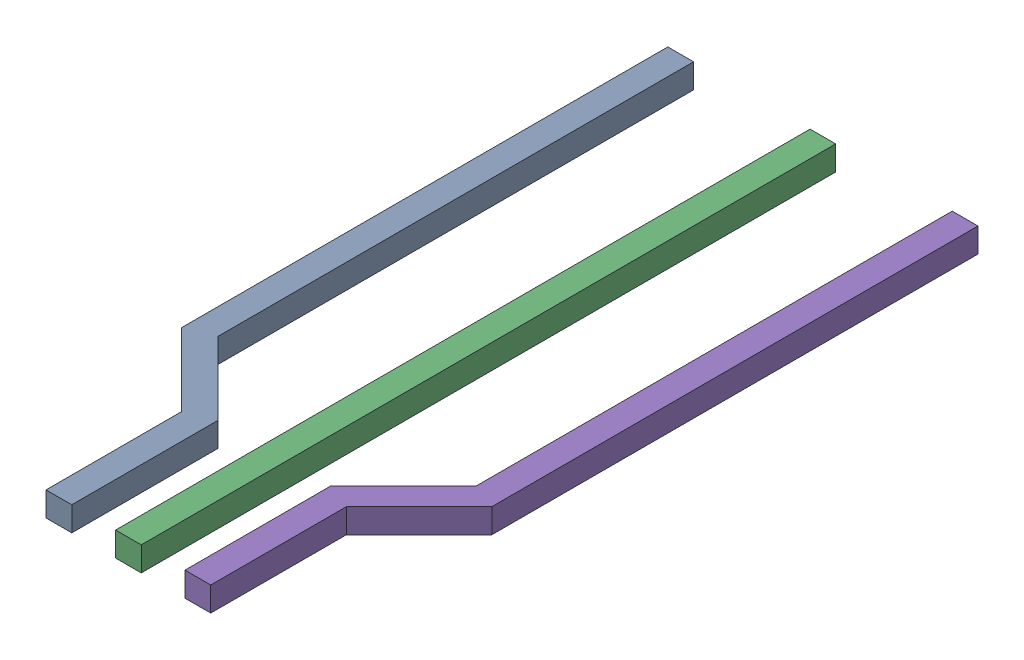
SolidWorks assembly Free-Models.step, configuration Default. Lengths in mm.
Overall size (5.68 0.46 12.71).
15 component instances, 4 part files, 0 mates.
Components (placement in the parent):
- PCB1.step-1: PCB1.step [Default] at (-1.2706 -0.1276 0) x (1 0 0) z (0 -1 0) size (1.81 12.71 0.46)
  - Free-Models-1.step-1: Free-Models-1.step [Default] at origin size (1.81 12.71 0.46)
    - 523779104.step-1: 523779104.step [Default] at (-0.665 -6.35 -0.35) size (1.81 12.71 0.46)
      - Extruded-43.step-1: Extruded-43.step [Default] at origin size (1.81 12.71 0.46)
  - Board-44.step-1: Board-44.step [Default] at (0 0 -0.2083) size (0.27 0.27 0.21)
- PCB2.step-1: PCB2.step [Default] at (0.0004 -0.1275 0) x (1 0 0) z (0 -1 0) size (0.47 12.7 0.45)
  - Free-Models-2.step-1: Free-Models-2.step [Default] at origin size (0.47 12.7 0.45)
    - 790454240.step-1: 790454240.step [Default] at (0 -6.35 -0.35) size (0.47 12.7 0.45)
      - Extruded-45.step-1: Extruded-45.step [Default] at origin size (0.47 12.7 0.45)
  - Board-46.step-1: Board-46.step [Default] at (0 0 -0.2083) size (0.27 0.27 0.21)
- PCB1.step-2: PCB1.step [Default] at (1.2705 0.1276 0) x (-1 0 0) z (0 1 0) size (1.81 12.71 0.46)
  - Free-Models-1.step-1: Free-Models-1.step [Default] at origin size (1.81 12.71 0.46)
    - 523779104.step-1: 523779104.step [Default] at (-0.665 -6.35 -0.35) size (1.81 12.71 0.46)
      - Extruded-43.step-1: Extruded-43.step [Default] at origin size (1.81 12.71 0.46)
  - Board-44.step-1: Board-44.step [Default] at (0 0 -0.2083) size (0.27 0.27 0.21)
